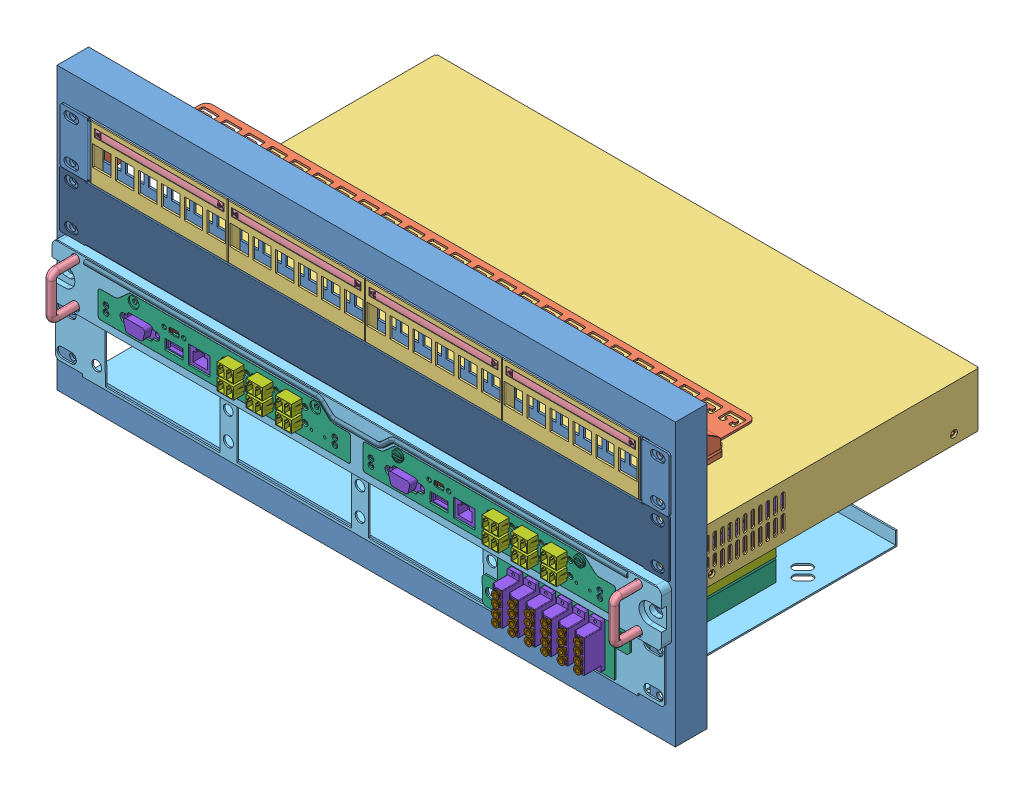
SolidWorks assembly Wandgehäuse, configuration Standard. Lengths in mm.
Overall size (490.07 223 300.15).
129 component instances, 28 part files, 12 mates.
Components (placement in the parent):
- Frame-1: Frame [Standard] at (-119.6021 40.1558 10.5) size (490 223 25)
- fod-assy_asm-1: fod-assy_asm [Standard] at (-119.0021 -4.0642 12.5) size (483 43.5 300.15)
  - FOD-BASE-1: FOD-BASE [Standard] at origin size (428 42.5 268.8)
  - FOD-TOP-COVER-1: FOD-TOP-COVER [Standard] at (0 43.5 -17) size (430.4 43 270)
  - PRT0002-1: PRT0002 [Standard] at (223 22 5) x (1 0 0) z (0 -1 0) size (6 25.15 37.6)
  - PRT0002-2: PRT0002 [Standard] at (-223 22 5) x (-1 0 0) z (0 1 0) size (6 25.15 37.6)
  - FOD-FRONT-PANEL-1: FOD-FRONT-PANEL [Standard] at (0 22 0) size (483 43.5 17)
  - FOD-MODULE-ASSY_ASM-1: FOD-MODULE-ASSY_ASM [Standard] at (-205 9 5) size (200 30 265.8)
    - FOD-IO-PANEL-1: FOD-IO-PANEL [Standard] at (0 -2.9 1) size (200 30 14)
    - CONN-LC-TYPE-SCREW-1: CONN-LC-TYPE-SCREW [Standard] at (109 12 11.3) x (-1 0 0) z (0 0 1) size (22 9.3 25.8)
    - CONN-LC-TYPE-SCREW-2: CONN-LC-TYPE-SCREW [Standard] at (132 12 11.3) x (-1 0 0) z (0 0 1) size (22 9.3 25.8)
    - CONN-LC-TYPE-SCREW-3: CONN-LC-TYPE-SCREW [Standard] at (155 12 11.3) x (-1 0 0) z (0 0 1) size (22 9.3 25.8)
    - CONN-LC-TYPE-SCREW-4: CONN-LC-TYPE-SCREW [Standard] at (109 23 11.3) x (-1 0 0) z (0 0 1) size (22 9.3 25.8)
    - CONN-LC-TYPE-SCREW-5: CONN-LC-TYPE-SCREW [Standard] at (132 23 11.3) x (-1 0 0) z (0 0 1) size (22 9.3 25.8)
    - CONN-LC-TYPE-SCREW-6: CONN-LC-TYPE-SCREW [Standard] at (155 23 11.3) x (-1 0 0) z (0 0 1) size (22 9.3 25.8)
    - FOD-MAIN-BD-1: FOD-MAIN-BD [Standard] at origin size (200 15.1 262)
      - FOD-MAIN-BD_3-1: FOD-MAIN-BD_3 [Standard] at origin size (200 15.1 262)
      - FOD-MAIN-BD_2-1: FOD-MAIN-BD_2 [Standard] at origin size (9.8 5.5 18.1)
      - FOD-MAIN-BD-1: FOD-MAIN-BD [Standard] at origin size (9.8 5.5 18.1)
    - SLIDE-SWITCH-1: SLIDE-SWITCH [Standard] at (60 14.5 -5) size (19 6 10.5)
    - FOD-BD-COVER-1: FOD-BD-COVER [Standard] at (100 7.6 -120) size (190 9 90)
  - FOD-MODULE-ASSY_ASM-2: FOD-MODULE-ASSY_ASM [Standard] at (5 9 5) size (200 30 265.8)
    - FOD-IO-PANEL-1: FOD-IO-PANEL [Standard] at (0 -2.9 1) size (200 30 14)
    - CONN-LC-TYPE-SCREW-1: CONN-LC-TYPE-SCREW [Standard] at (109 12 11.3) x (-1 0 0) z (0 0 1) size (22 9.3 25.8)
    - CONN-LC-TYPE-SCREW-2: CONN-LC-TYPE-SCREW [Standard] at (132 12 11.3) x (-1 0 0) z (0 0 1) size (22 9.3 25.8)
    - CONN-LC-TYPE-SCREW-3: CONN-LC-TYPE-SCREW [Standard] at (155 12 11.3) x (-1 0 0) z (0 0 1) size (22 9.3 25.8)
    - CONN-LC-TYPE-SCREW-4: CONN-LC-TYPE-SCREW [Standard] at (109 23 11.3) x (-1 0 0) z (0 0 1) size (22 9.3 25.8)
    - CONN-LC-TYPE-SCREW-5: CONN-LC-TYPE-SCREW [Standard] at (132 23 11.3) x (-1 0 0) z (0 0 1) size (22 9.3 25.8)
    - CONN-LC-TYPE-SCREW-6: CONN-LC-TYPE-SCREW [Standard] at (155 23 11.3) x (-1 0 0) z (0 0 1) size (22 9.3 25.8)
    - FOD-MAIN-BD-1: FOD-MAIN-BD [Standard] at origin size (200 15.1 262)
      - FOD-MAIN-BD_3-1: FOD-MAIN-BD_3 [Standard] at origin size (200 15.1 262)
      - FOD-MAIN-BD_2-1: FOD-MAIN-BD_2 [Standard] at origin size (9.8 5.5 18.1)
      - FOD-MAIN-BD-1: FOD-MAIN-BD [Standard] at origin size (9.8 5.5 18.1)
    - SLIDE-SWITCH-1: SLIDE-SWITCH [Standard] at (60 14.5 -5) size (19 6 10.5)
    - FOD-BD-COVER-1: FOD-BD-COVER [Standard] at (100 7.6 -120) size (190 9 90)
  - FOD-PCB-GUIDE-1: FOD-PCB-GUIDE [Standard] at (-202.7 1 -5) size (7 14 235)
  - FOD-PCB-GUIDE-2: FOD-PCB-GUIDE [Standard] at (7.3 1 -5) size (7 14 235)
  - FOD-PCB-GUIDE-3: FOD-PCB-GUIDE [Standard] at (-7.3 1 -250) x (-1 0 0) z (0 0 -1) size (7 14 235)
  - FOD-PCB-GUIDE-4: FOD-PCB-GUIDE [Standard] at (202.7 1 -250) x (-1 0 0) z (0 0 -1) size (7 14 235)
  - FOD-DESIGN-BAR-1: FOD-DESIGN-BAR [Standard] at (0 41.9 6) size (430 13.1 3.5)
  - FOD-CAP-SCREW-1: FOD-CAP-SCREW [Standard] at (177 31.1 7) size (8 8 15)
  - FOD-CAP-SCREW-2: FOD-CAP-SCREW [Standard] at (33 31.1 7) size (8 8 15)
  - FOD-FRONT-BRKT-1: FOD-FRONT-BRKT [Standard] at (0 38.7 0) size (370 13 11)
  - FOD-SIDE-BRKT-1: FOD-SIDE-BRKT [Standard] at (213 37 0) x (-1 0 0) z (0 0 1) size (7.8 31 12)
  - FOD-SIDE-BRKT-2: FOD-SIDE-BRKT [Standard] at (-213 6 0) size (7.8 31 12)
  - FOD-BP-BD-ST-1: FOD-BP-BD-ST [Standard] at (-5 9 -254.8) x (1 0 0) z (0 -1 0) size (270 24.5 30)
  - SLIDE-SWITCH-1: SLIDE-SWITCH [Standard] at (177 25 -261.8) x (1 0 0) z (0 0 -1) size (19 6 10.5)
  - SLIDE-SWITCH-2: SLIDE-SWITCH [Standard] at (-177 19 -261.8) x (-1 0 0) z (0 0 -1) size (19 6 10.5)
- Keystone-Pannel-1: Keystone-Pannel [Standard] at (121.8487 128.6357 14) x (1 -0.000022 0) z (0 0 1) size (482.6 43.7 92.75)
  - 19-Keystone-Pannel-Front-1: 19-Keystone-Pannel-Front [Standard] at (-241.3 -21.8 -9.9) size (482.6 43.6 9.9)
  - 19-Keystone-Pannel-Back-1: 19-Keystone-Pannel-Back [Standard] at (-241.3 -21.7 -64.5) size (442.58 43.6 90.8)
  - Keystone-Pannel-6-Module-1: Keystone-Pannel-6-Module [Standard] at (-349.7 0 0) size (108.7 43.6 8.85)
    - 19-Keystone-Pannel-Einsatz-1: 19-Keystone-Pannel-Einsatz [Standard] at (-54.35 -21.8 -8.4) size (108.7 43.6 8.4)
    - 19-Keystone-Pannel-Glas-1: 19-Keystone-Pannel-Glas [Standard] at (-54.1 -7 -1) size (104 5.8 1.45)
  - Keystone-Pannel-6-Module-2: Keystone-Pannel-6-Module [Standard] at (-241 0 0) size (108.7 43.6 8.85)
    - 19-Keystone-Pannel-Einsatz-1: 19-Keystone-Pannel-Einsatz [Standard] at (-54.35 -21.8 -8.4) size (108.7 43.6 8.4)
    - 19-Keystone-Pannel-Glas-1: 19-Keystone-Pannel-Glas [Standard] at (-54.1 -7 -1) size (104 5.8 1.45)
  - Keystone-Pannel-6-Module-3: Keystone-Pannel-6-Module [Standard] at (-132.3 0 0) size (108.7 43.6 8.85)
    - 19-Keystone-Pannel-Einsatz-1: 19-Keystone-Pannel-Einsatz [Standard] at (-54.35 -21.8 -8.4) size (108.7 43.6 8.4)
    - 19-Keystone-Pannel-Glas-1: 19-Keystone-Pannel-Glas [Standard] at (-54.1 -7 -1) size (104 5.8 1.45)
  - Keystone-Pannel-6-Module-4: Keystone-Pannel-6-Module [Standard] at (-23.6 0 0) size (108.7 43.6 8.85)
    - 19-Keystone-Pannel-Einsatz-1: 19-Keystone-Pannel-Einsatz [Standard] at (-54.35 -21.8 -8.4) size (108.7 43.6 8.4)
    - 19-Keystone-Pannel-Glas-1: 19-Keystone-Pannel-Glas [Standard] at (-54.1 -7 -1) size (104 5.8 1.45)
- MTP-Pannel-1: MTP-Pannel [Standard] at (117.9275 -2.0722 13.7) x (0.999997 0.002386 0) z (0 0 1) size (482.6 47.8 225.51)
  - 1U Rack Plate-1: 1U Rack Plate [Standard] at (-414.8398 -8.3387 0) size (482.6 47.8 205.5)
  - MTP-Casette-1: MTP-Casette [Standard] at (-26.275 -1.825 1.2) size (117 43.2 150.01)
    - Cassette-1: Cassette [Standard] at (-81.5544 -7.2939 -1.2) size (117 43.2 131.2)
    - Cassette Lid-1: Cassette Lid [Standard] at (-38.8731 -6.65 -32.039) size (86.6 20.2 130)
    - LC-Adapter-1: LC-Adapter [Standard] at (-94.18 -5.525 16.25) x (0 1 0) z (0 0 1) size (34.9 10.05 34.47)
      - LC Adaptor-1: LC Adaptor [Standard] at (-28.4856 -9.35 -16.25) x (1 0 0) z (0 -1 0) size (34.9 25.75 9.35)
      - LC Adaptor Dust Cap-1: LC Adaptor Dust Cap [Standard] at (-27.05 -6.075 2.56) x (-0.837169 0.546944 0) z (-0.546944 -0.837169 0) size (5.75 16.66 5.75)
      - LC Adaptor Dust Cap-2: LC Adaptor Dust Cap [Standard] at (-20.85 -6.075 2.56) x (-0.837169 0.546944 0) z (-0.546944 -0.837169 0) size (5.75 16.66 5.75)
      - LC Adaptor Dust Cap-3: LC Adaptor Dust Cap [Standard] at (-14.05 -6.075 2.56) x (-0.837169 0.546944 0) z (-0.546944 -0.837169 0) size (5.75 16.66 5.75)
      - LC Adaptor Dust Cap-4: LC Adaptor Dust Cap [Standard] at (-7.85 -6.075 2.56) x (-0.837169 0.546944 0) z (-0.546944 -0.837169 0) size (5.75 16.66 5.75)
      - LC Adaptor Dust Cap-5: LC Adaptor Dust Cap [Standard] at (-27.05 -6.075 -31.91) x (0.972668 -0.232198 0) z (-0.232198 -0.972668 0) size (5.75 16.66 5.75)
      - LC Adaptor Dust Cap-6: LC Adaptor Dust Cap [Standard] at (-20.85 -6.075 -31.91) x (1 0 0) z (0 -1 0) size (5.75 16.66 5.75)
      - LC Adaptor Dust Cap-7: LC Adaptor Dust Cap [Standard] at (-14.05 -6.075 -31.91) x (0.97427 0.225385 0) z (0.225385 -0.97427 0) size (5.75 16.66 5.75)
      - LC Adaptor Dust Cap-8: LC Adaptor Dust Cap [Standard] at (-7.85 -6.075 -31.91) x (1 0 0) z (0 -1 0) size (5.75 16.66 5.75)
    - LC-Adapter-2: LC-Adapter [Standard] at (-81.18 -5.525 16.25) x (0 1 0) z (0 0 1) size (34.9 10.05 34.47)
      - LC Adaptor-1: LC Adaptor [Standard] at (-28.4856 -9.35 -16.25) x (1 0 0) z (0 -1 0) size (34.9 25.75 9.35)
      - LC Adaptor Dust Cap-1: LC Adaptor Dust Cap [Standard] at (-27.05 -6.075 2.56) x (-0.837169 0.546944 0) z (-0.546944 -0.837169 0) size (5.75 16.66 5.75)
      - LC Adaptor Dust Cap-2: LC Adaptor Dust Cap [Standard] at (-20.85 -6.075 2.56) x (-0.837169 0.546944 0) z (-0.546944 -0.837169 0) size (5.75 16.66 5.75)
      - LC Adaptor Dust Cap-3: LC Adaptor Dust Cap [Standard] at (-14.05 -6.075 2.56) x (-0.837169 0.546944 0) z (-0.546944 -0.837169 0) size (5.75 16.66 5.75)
      - LC Adaptor Dust Cap-4: LC Adaptor Dust Cap [Standard] at (-7.85 -6.075 2.56) x (-0.837169 0.546944 0) z (-0.546944 -0.837169 0) size (5.75 16.66 5.75)
      - LC Adaptor Dust Cap-5: LC Adaptor Dust Cap [Standard] at (-27.05 -6.075 -31.91) x (0.972668 -0.232198 0) z (-0.232198 -0.972668 0) size (5.75 16.66 5.75)
      - LC Adaptor Dust Cap-6: LC Adaptor Dust Cap [Standard] at (-20.85 -6.075 -31.91) x (1 0 0) z (0 -1 0) size (5.75 16.66 5.75)
      - LC Adaptor Dust Cap-7: LC Adaptor Dust Cap [Standard] at (-14.05 -6.075 -31.91) x (0.97427 0.225385 0) z (0.225385 -0.97427 0) size (5.75 16.66 5.75)
      - LC Adaptor Dust Cap-8: LC Adaptor Dust Cap [Standard] at (-7.85 -6.075 -31.91) x (1 0 0) z (0 -1 0) size (5.75 16.66 5.75)
    - LC-Adapter-3: LC-Adapter [Standard] at (-68.18 -5.525 16.25) x (0 1 0) z (0 0 1) size (34.9 10.05 34.47)
      - LC Adaptor-1: LC Adaptor [Standard] at (-28.4856 -9.35 -16.25) x (1 0 0) z (0 -1 0) size (34.9 25.75 9.35)
      - LC Adaptor Dust Cap-1: LC Adaptor Dust Cap [Standard] at (-27.05 -6.075 2.56) x (-0.837169 0.546944 0) z (-0.546944 -0.837169 0) size (5.75 16.66 5.75)
      - LC Adaptor Dust Cap-2: LC Adaptor Dust Cap [Standard] at (-20.85 -6.075 2.56) x (-0.837169 0.546944 0) z (-0.546944 -0.837169 0) size (5.75 16.66 5.75)
      - LC Adaptor Dust Cap-3: LC Adaptor Dust Cap [Standard] at (-14.05 -6.075 2.56) x (-0.837169 0.546944 0) z (-0.546944 -0.837169 0) size (5.75 16.66 5.75)
      - LC Adaptor Dust Cap-4: LC Adaptor Dust Cap [Standard] at (-7.85 -6.075 2.56) x (-0.837169 0.546944 0) z (-0.546944 -0.837169 0) size (5.75 16.66 5.75)
      - LC Adaptor Dust Cap-5: LC Adaptor Dust Cap [Standard] at (-27.05 -6.075 -31.91) x (0.972668 -0.232198 0) z (-0.232198 -0.972668 0) size (5.75 16.66 5.75)
      - LC Adaptor Dust Cap-6: LC Adaptor Dust Cap [Standard] at (-20.85 -6.075 -31.91) x (1 0 0) z (0 -1 0) size (5.75 16.66 5.75)
      - LC Adaptor Dust Cap-7: LC Adaptor Dust Cap [Standard] at (-14.05 -6.075 -31.91) x (0.97427 0.225385 0) z (0.225385 -0.97427 0) size (5.75 16.66 5.75)
      - LC Adaptor Dust Cap-8: LC Adaptor Dust Cap [Standard] at (-7.85 -6.075 -31.91) x (1 0 0) z (0 -1 0) size (5.75 16.66 5.75)
    - LC-Adapter-4: LC-Adapter [Standard] at (-55.18 -5.525 16.25) x (0 1 0) z (0 0 1) size (34.9 10.05 34.47)
      - LC Adaptor-1: LC Adaptor [Standard] at (-28.4856 -9.35 -16.25) x (1 0 0) z (0 -1 0) size (34.9 25.75 9.35)
      - LC Adaptor Dust Cap-1: LC Adaptor Dust Cap [Standard] at (-27.05 -6.075 2.56) x (-0.837169 0.546944 0) z (-0.546944 -0.837169 0) size (5.75 16.66 5.75)
      - LC Adaptor Dust Cap-2: LC Adaptor Dust Cap [Standard] at (-20.85 -6.075 2.56) x (-0.837169 0.546944 0) z (-0.546944 -0.837169 0) size (5.75 16.66 5.75)
      - LC Adaptor Dust Cap-3: LC Adaptor Dust Cap [Standard] at (-14.05 -6.075 2.56) x (-0.837169 0.546944 0) z (-0.546944 -0.837169 0) size (5.75 16.66 5.75)
      - LC Adaptor Dust Cap-4: LC Adaptor Dust Cap [Standard] at (-7.85 -6.075 2.56) x (-0.837169 0.546944 0) z (-0.546944 -0.837169 0) size (5.75 16.66 5.75)
      - LC Adaptor Dust Cap-5: LC Adaptor Dust Cap [Standard] at (-27.05 -6.075 -31.91) x (0.972668 -0.232198 0) z (-0.232198 -0.972668 0) size (5.75 16.66 5.75)
      - LC Adaptor Dust Cap-6: LC Adaptor Dust Cap [Standard] at (-20.85 -6.075 -31.91) x (1 0 0) z (0 -1 0) size (5.75 16.66 5.75)
      - LC Adaptor Dust Cap-7: LC Adaptor Dust Cap [Standard] at (-14.05 -6.075 -31.91) x (0.97427 0.225385 0) z (0.225385 -0.97427 0) size (5.75 16.66 5.75)
      - LC Adaptor Dust Cap-8: LC Adaptor Dust Cap [Standard] at (-7.85 -6.075 -31.91) x (1 0 0) z (0 -1 0) size (5.75 16.66 5.75)
    - LC-Adapter-5: LC-Adapter [Standard] at (-42.18 -5.525 16.25) x (0 1 0) z (0 0 1) size (34.9 10.05 34.47)
      - LC Adaptor-1: LC Adaptor [Standard] at (-28.4856 -9.35 -16.25) x (1 0 0) z (0 -1 0) size (34.9 25.75 9.35)
      - LC Adaptor Dust Cap-1: LC Adaptor Dust Cap [Standard] at (-27.05 -6.075 2.56) x (-0.837169 0.546944 0) z (-0.546944 -0.837169 0) size (5.75 16.66 5.75)
      - LC Adaptor Dust Cap-2: LC Adaptor Dust Cap [Standard] at (-20.85 -6.075 2.56) x (-0.837169 0.546944 0) z (-0.546944 -0.837169 0) size (5.75 16.66 5.75)
      - LC Adaptor Dust Cap-3: LC Adaptor Dust Cap [Standard] at (-14.05 -6.075 2.56) x (-0.837169 0.546944 0) z (-0.546944 -0.837169 0) size (5.75 16.66 5.75)
      - LC Adaptor Dust Cap-4: LC Adaptor Dust Cap [Standard] at (-7.85 -6.075 2.56) x (-0.837169 0.546944 0) z (-0.546944 -0.837169 0) size (5.75 16.66 5.75)
      - LC Adaptor Dust Cap-5: LC Adaptor Dust Cap [Standard] at (-27.05 -6.075 -31.91) x (0.972668 -0.232198 0) z (-0.232198 -0.972668 0) size (5.75 16.66 5.75)
      - LC Adaptor Dust Cap-6: LC Adaptor Dust Cap [Standard] at (-20.85 -6.075 -31.91) x (1 0 0) z (0 -1 0) size (5.75 16.66 5.75)
      - LC Adaptor Dust Cap-7: LC Adaptor Dust Cap [Standard] at (-14.05 -6.075 -31.91) x (0.97427 0.225385 0) z (0.225385 -0.97427 0) size (5.75 16.66 5.75)
      - LC Adaptor Dust Cap-8: LC Adaptor Dust Cap [Standard] at (-7.85 -6.075 -31.91) x (1 0 0) z (0 -1 0) size (5.75 16.66 5.75)
    - LC-Adapter-6: LC-Adapter [Standard] at (-29.18 -5.525 16.25) x (0 1 0) z (0 0 1) size (34.9 10.05 34.47)
      - LC Adaptor-1: LC Adaptor [Standard] at (-28.4856 -9.35 -16.25) x (1 0 0) z (0 -1 0) size (34.9 25.75 9.35)
      - LC Adaptor Dust Cap-1: LC Adaptor Dust Cap [Standard] at (-27.05 -6.075 2.56) x (-0.837169 0.546944 0) z (-0.546944 -0.837169 0) size (5.75 16.66 5.75)
      - LC Adaptor Dust Cap-2: LC Adaptor Dust Cap [Standard] at (-20.85 -6.075 2.56) x (-0.837169 0.546944 0) z (-0.546944 -0.837169 0) size (5.75 16.66 5.75)
      - LC Adaptor Dust Cap-3: LC Adaptor Dust Cap [Standard] at (-14.05 -6.075 2.56) x (-0.837169 0.546944 0) z (-0.546944 -0.837169 0) size (5.75 16.66 5.75)
      - LC Adaptor Dust Cap-4: LC Adaptor Dust Cap [Standard] at (-7.85 -6.075 2.56) x (-0.837169 0.546944 0) z (-0.546944 -0.837169 0) size (5.75 16.66 5.75)
      - LC Adaptor Dust Cap-5: LC Adaptor Dust Cap [Standard] at (-27.05 -6.075 -31.91) x (0.972668 -0.232198 0) z (-0.232198 -0.972668 0) size (5.75 16.66 5.75)
      - LC Adaptor Dust Cap-6: LC Adaptor Dust Cap [Standard] at (-20.85 -6.075 -31.91) x (1 0 0) z (0 -1 0) size (5.75 16.66 5.75)
      - LC Adaptor Dust Cap-7: LC Adaptor Dust Cap [Standard] at (-14.05 -6.075 -31.91) x (0.97427 0.225385 0) z (0.225385 -0.97427 0) size (5.75 16.66 5.75)
      - LC Adaptor Dust Cap-8: LC Adaptor Dust Cap [Standard] at (-7.85 -6.075 -31.91) x (1 0 0) z (0 -1 0) size (5.75 16.66 5.75)
- Intellinet_712675-1: Intellinet_712675 [Standard] at (54.8488 40.1321 12.5) x (1 -0.000022 0) z (0 0 1) size (483 44.5 9)
Mates (geometry in assembly coordinates):
- Deckungsgleich1: coincident anti-aligned: plane of Frame-1 through (-119.6021 40.1558 12.5) normal (0 0 1); plane of fod-assy_asm-1/FOD-FRONT-PANEL-1 through (-360.5021 -4.0642 12.5) normal (0 0 -1)
- Langloch1: slot aligned: cylinder of Frame-1 through (-352.1521 17.9358 12.5) axis (0 0 -1) radius 2.5; cylinder of fod-assy_asm-1/FOD-FRONT-PANEL-1 through (-350.5021 17.9358 20.5) axis (0 0 -1) radius 3.6; cylinder of fod-assy_asm-1/FOD-FRONT-PANEL-1 through (-353.8021 17.9358 20.5) axis (0 0 -1) radius 3.6
- Langloch2: slot anti-aligned: cylinder of Frame-1 through (112.9479 17.9358 12.5) axis (0 0 -1) radius 2.5; cylinder of fod-assy_asm-1/FOD-FRONT-PANEL-1 through (112.4979 17.9358 20.5) axis (0 0 1) radius 3.6; cylinder of fod-assy_asm-1/FOD-FRONT-PANEL-1 through (115.7979 17.9358 20.5) axis (0 0 1) radius 3.6
- Deckungsgleich2: coincident anti-aligned: plane of Frame-1 through (-119.6021 40.1558 12.5) normal (0 0 1); plane of Keystone-Pannel-1/19-Keystone-Pannel-Front-1 through (-112.4075 106.8407 12.5) normal (0 0 -1)
- Langloch3: slot aligned: cylinder of Keystone-Pannel-1/19-Keystone-Pannel-Front-1 through (-354.3514 122.7159 14) axis (0 0 -1) radius 3.25; cylinder of Frame-1 through (-352.1521 122.7158 12.5) axis (0 0 -1) radius 2.5; cylinder of Keystone-Pannel-1/19-Keystone-Pannel-Front-1 through (-349.3514 122.7158 14) axis (0 0 -1) radius 3.25
- Langloch4: slot aligned: cylinder of Keystone-Pannel-1/19-Keystone-Pannel-Front-1 through (110.4479 90.9559 14) axis (0 0 -1) radius 3.25; cylinder of Frame-1 through (112.9479 90.9558 12.5) axis (0 0 -1) radius 2.5; cylinder of Keystone-Pannel-1/19-Keystone-Pannel-Front-1 through (115.4479 90.9558 14) axis (0 0 -1) radius 3.25
- Deckungsgleich3: coincident: plane of Frame-1 through (-119.6021 40.1558 12.5) normal (0 0 1); plane of MTP-Pannel-1/1U Rack Plate-1 through (-296.8912 -11.4009 12.5) normal (0 0 -1)
- Konzentrisch2: concentric: cylinder of Frame-1 through (112.9479 -10.6342 12.5) axis (0 0 -1) radius 2.5; cylinder of MTP-Pannel-1/1U Rack Plate-1 through (112.9479 -10.6342 12.3) axis (0 0 1) radius 3.95
- Abstand1: distance = 4 mm: cylinder of Frame-1 through (-352.1521 -42.3942 12.5) axis (0 0 -1) radius 2.5; plane of MTP-Pannel-1/1U Rack Plate-1 through (-352.0681 -46.394 12.3) normal (-0.002386 0.999997 0)
- Langloch5: slot: cylinder of Intellinet_712675-1 through (110.4973 46.5059 13.7) axis (0 0 -1) radius 3.4; cylinder of Frame-1 through (112.9479 46.5058 12.5) axis (0 0 -1) radius 2.5; cylinder of Intellinet_712675-1 through (114.1973 46.5058 43.0711) axis (0 0 -1) radius 3.4
- Langloch6: slot: cylinder of Intellinet_712675-1 through (-354.0021 78.2659 13.7) axis (0 0 -1) radius 3.4; cylinder of Frame-1 through (-352.1521 78.2658 12.5) axis (0 0 -1) radius 2.5; cylinder of Intellinet_712675-1 through (-350.3021 78.2658 43.0711) axis (0 0 -1) radius 3.4
- Deckungsgleich4: coincident anti-aligned: plane of Frame-1 through (-119.6021 40.1558 12.5) normal (0 0 1); plane of Intellinet_712675-1 through (-119.9024 62.3859 12.5) normal (0 0 -1)
